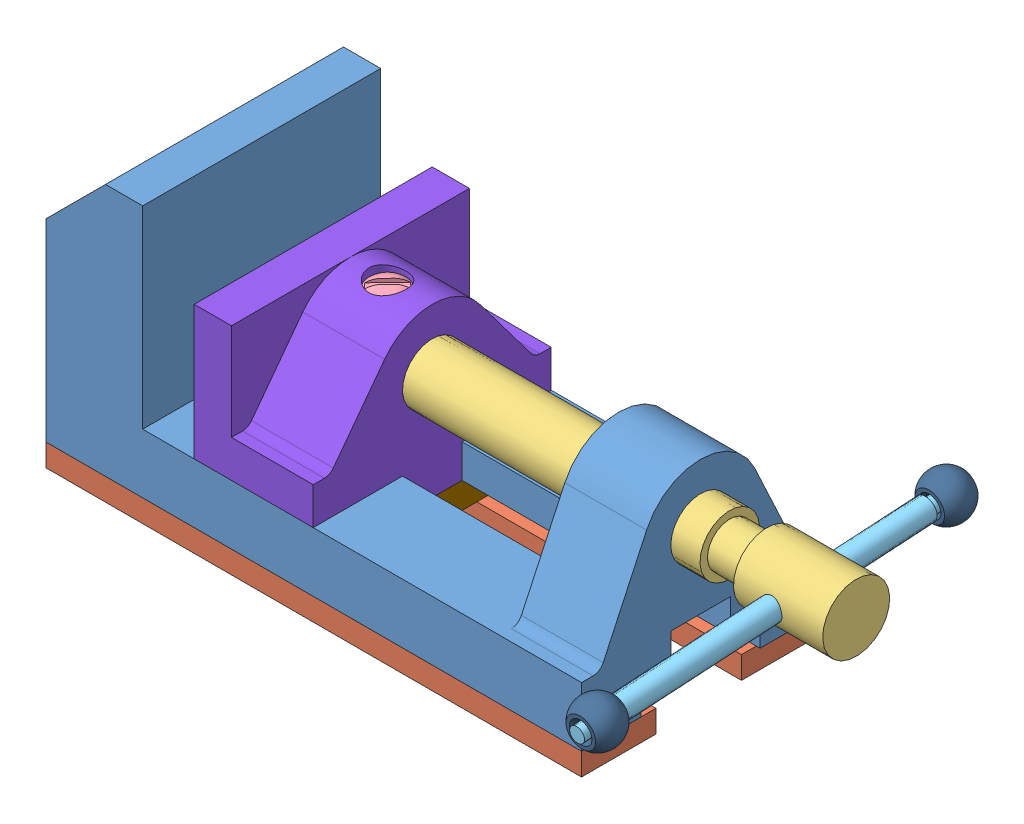
SolidWorks assembly Assem1, configuration Default. Lengths in mm.
Overall size (186.85 74 104.42).
16 component instances, 10 part files, 29 mates.
Components (placement in the parent):
- Base-1: Base [Default] at (59.8708 54.8937 103.399) size (144 68 64)
- Base Plate-1: Base Plate [Default] at (59.8708 43.8937 125.399) x (-1 0 0) z (0 -1 0) size (144 20 6)
- Jaw Screw-1: Jaw Screw [Default] at (104.7197 82.8937 103.399) x (1 0 0) z (0 -0.998152 -0.060769) size (138 18 18)
- Oval Filister-1: Oval Filister [Default] at (47.7197 91.7359 103.3967) x (-0.720326 0.000228 -0.693636) z (0.693636 0.000237 -0.720326) size (10 11.89 10)
- Screw Bar-1: Screw Bar [Default] at (159.7197 82.337 112.5435) x (0 -0.060769 0.998152) z (0.871066 0.490258 0.029848) size (104 6 6)
- Screw Set 1-1: Screw Set 1 [Default] at (23.8708 50.3937 81.399) x (0.921057 0 -0.389428) z (-0.389428 0 -0.921057) size (12 17.73 11.83)
- Screw Set 2-1: Screw Set 2 [Default] at (35.7197 60.8937 103.399) x (-0.982017 0 -0.188793) z (-0.188793 0 0.982017) size (15.87 24.73 16)
- Vice Jaw-1: Vice Jaw [Default] at (43.7197 57.8937 103.399) x (0 0 -1) z (1 0 0) size (64 45 32)
- Clamping Plate-1: Clamping Plate [Default] at (43.7197 50.3937 103.399) x (1 0 0) z (0 0 -1) size (32 7 32)
- Base Plate-4: Base Plate [Default] at (58.8708 43.8937 81.399) x (1 0 0) z (0 -1 0) size (144 20 6)
- Screw Set 2-2: Screw Set 2 [Default] at (51.7197 60.8937 103.399) x (-0.982017 0 -0.188793) z (-0.188793 0 0.982017) size (15.87 24.73 16)
- Screw Set 1-2: Screw Set 1 [Default] at (23.8708 50.3937 125.399) x (0.921057 0 -0.389428) z (-0.389428 0 -0.921057) size (12 17.73 11.83)
- Screw Set 1-3: Screw Set 1 [Default] at (93.8708 50.3937 81.399) x (0.921057 0 -0.389428) z (-0.389428 0 -0.921057) size (12 17.73 11.83)
- Screw Set 1-4: Screw Set 1 [Default] at (93.8708 50.3937 125.399) x (0.921057 0 -0.389428) z (-0.389428 0 -0.921057) size (12 17.73 11.83)
- bar gloves-1: bar gloves [Default] at (159.7197 85.2235 65.1313) x (0 0.060769 -0.998152) z (1 0 0) size (9 12 12)
- bar gloves-2: bar gloves [Default] at (159.7197 79.5112 158.9576) x (0 0.060769 -0.998152) z (1 0 0) size (9 12 12)
Mates (geometry in assembly coordinates):
- Coincident4: coincident anti-aligned: plane of Base-1 through (-12.1292 53.8937 111.399) normal (0 0 -1); plane of Vice Jaw-1 through (26.7197 62.8937 111.399) normal (0 0 1)
- Coincident5: coincident anti-aligned: plane of Base-1 through (-12.1292 53.8937 95.399) normal (0 0 1); plane of Vice Jaw-1 through (26.7197 53.8937 95.399) normal (0 0 -1)
- Coincident6: coincident anti-aligned: plane of Base-1 through (-12.1292 62.8937 135.399) normal (0 1 0); plane of Vice Jaw-1 through (26.7197 62.8937 135.399) normal (0 -1 0)
- Coincident7: coincident anti-aligned: circle of Base-1; cylinder of Jaw Screw-1 through (35.7197 82.8937 103.399) axis (-1 0 0) radius 8
- Coincident8: coincident anti-aligned: plane of Jaw Screw-1 through (35.7197 82.8937 103.399) normal (-1 0 0); circle of Vice Jaw-1
- Concentric1: concentric aligned: cylinder of Oval Filister-1 through (47.7197 96.7359 103.3983) axis (0 1 0.000329) radius 3.33; cone of Vice Jaw-1 through (47.7197 88.9062 103.3957) axis (0 1 0.000329)
- Concentric2: concentric aligned: cylinder of Oval Filister-1 through (47.7197 96.7359 103.3983) axis (0 1 0.000329) radius 5; cone of Vice Jaw-1 through (47.7197 95.9069 103.398) axis (0 1 0.000329)
- Concentric3: concentric aligned: cylinder of Oval Filister-1 through (47.7197 96.7359 103.3983) axis (0 1 0.000329) radius 5; cone of Vice Jaw-1 through (47.7197 95.9069 103.398) axis (0 1 0.000329)
- Coincident13: coincident anti-aligned: line of Base-1 through (-12.1292 46.8937 135.399) axis (1 0 0); line of Base Plate-1 through (131.8708 46.8937 135.399) axis (-1 0 0)
- Coincident14: coincident anti-aligned: plane of Base-1 through (-12.1292 46.8937 135.399) normal (0 -1 0); plane of Base Plate-1 through (59.8708 46.8937 125.399) normal (0 1 0)
- Coincident15: coincident anti-aligned: line of Base-1 through (131.8708 46.8937 135.399) axis (0 0 -1); line of Base Plate-1 through (131.8708 46.8937 115.399) axis (0 0 1)
- Coincident16: coincident anti-aligned: plane of Vice Jaw-1 through (26.7197 53.8937 111.399) normal (0 -1 0); plane of Clamping Plate-1 through (43.7197 53.8937 103.399) normal (0 1 0)
- Concentric4: concentric anti-aligned: circle of Vice Jaw-1; circle of Clamping Plate-1
- Concentric5: concentric aligned: circle of Vice Jaw-1; circle of Clamping Plate-1
- Concentric6: concentric aligned: cylinder of Screw Set 2-1 through (35.7197 51.8937 103.399) axis (0 -1 0) radius 3; cylinder of Vice Jaw-1 through (35.7197 53.8937 103.399) axis (0 -1 0) radius 3
- Concentric7: concentric aligned: cone of Screw Set 2-1 through (35.7197 51.8937 103.399) axis (0 1 0); cone of Clamping Plate-1 through (35.7197 51.8937 103.399) axis (0 1 0)
- Coincident17: coincident anti-aligned: plane of Base-1 through (-12.1292 46.8937 135.399) normal (0 -1 0); plane of Base Plate-4 through (58.8708 46.8937 81.399) normal (0 1 0)
- Concentric8: concentric anti-aligned: cylinder of Base-1 through (23.8708 46.8937 81.399) axis (0 -1 0) radius 3; cylinder of Base Plate-4 through (23.8708 40.8937 81.399) axis (0 1 0) radius 3.5
- Concentric9: concentric anti-aligned: cylinder of Base-1 through (93.8708 46.8937 81.399) axis (0 -1 0) radius 3; cylinder of Base Plate-4 through (93.8708 40.8937 81.399) axis (0 1 0) radius 3.5
- Coincident19: coincident aligned: plane of Screw Set 2-1 through (35.7197 46.8937 103.399) normal (0 -1 0); plane of Clamping Plate-1 through (43.7197 46.8937 103.399) normal (0 -1 0)
- Concentric10: concentric aligned: cylinder of Vice Jaw-1 through (51.7197 53.8937 103.399) axis (0 -1 0) radius 3; cylinder of Screw Set 2-2 through (51.7197 51.8937 103.399) axis (0 -1 0) radius 3
- Coincident20: coincident aligned: plane of Clamping Plate-1 through (43.7197 46.8937 103.399) normal (0 -1 0); plane of Screw Set 2-2 through (51.7197 46.8937 103.399) normal (0 -1 0)
- Coincident21: coincident anti-aligned: circle of Base-1; cylinder of Screw Set 1-1 through (23.8708 43.8937 81.399) axis (0 1 0) radius 3
- Coincident22: coincident aligned: plane of Screw Set 1-1 through (23.8708 40.8937 81.399) normal (0 -1 0); plane of Base Plate-4 through (58.8708 40.8937 81.399) normal (0 -1 0)
- Concentric12: concentric anti-aligned: cylinder of Jaw Screw-1 through (159.7197 84.018 84.9332) axis (0 -0.060769 0.998152) radius 3; cylinder of Screw Bar-1 through (159.7197 85.497 60.6396) axis (0 0.060769 -0.998152) radius 3
- Concentric13: concentric anti-aligned: cylinder of Screw Bar-1 through (159.7197 85.497 60.6396) axis (0 0.060769 -0.998152) radius 2; cylinder of bar gloves-1 through (159.7197 84.9501 69.623) axis (0 -0.060769 0.998152) radius 2
- Coincident23: coincident aligned: plane of Screw Bar-1 through (159.7197 85.497 60.6396) normal (0 0.060769 -0.998152); plane of bar gloves-1 through (159.7197 81.5357 60.3985) normal (0 0.060769 -0.998152)
- Concentric14: concentric: cylinder of Screw Bar-1 through (159.7197 85.497 60.6396) axis (0 0.060769 -0.998152) radius 2; cylinder of bar gloves-2 through (159.7197 79.2377 163.4493) axis (0 -0.060769 0.998152) radius 2
- Coincident24: coincident anti-aligned: plane of Screw Bar-1 through (160.702 78.0458 154.36) normal (0 -0.060769 0.998152); plane of bar gloves-2 through (159.7197 75.8234 154.2247) normal (0 0.060769 -0.998152)
